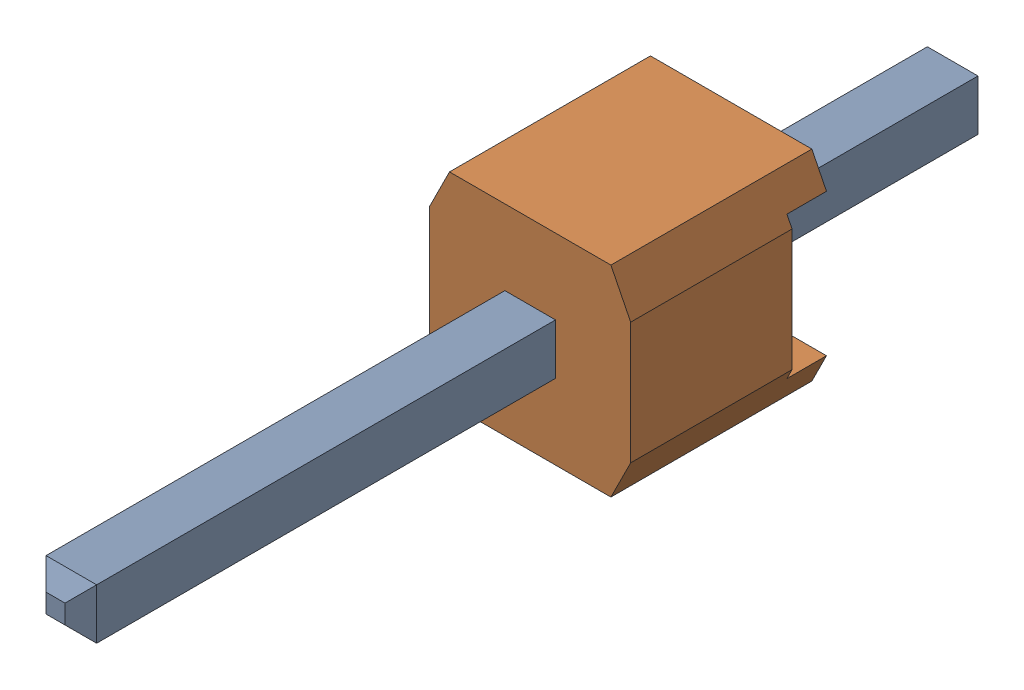
SolidWorks assembly C3_1, configuration Default. Lengths in mm.
Overall size (2.54 2.54 11.54).
3 component instances, 2 part files, 0 mates.
Components (placement in the parent):
- 61300111121-1: 61300111121 [Default] at (19.9391 25.0191 1.27) x (1 0 0) z (0 -1 0) size (2.54 11.54 2.54)
  - 6130xx11121_PIN-1: 6130xx11121_PIN [Default] at (0 1.5 0) x (1 0 0) z (0 -1 0) size (0.64 0.64 11.54)
  - 61300111121-1: 61300111121 [Default] at origin size (2.54 2.54 2.54)
